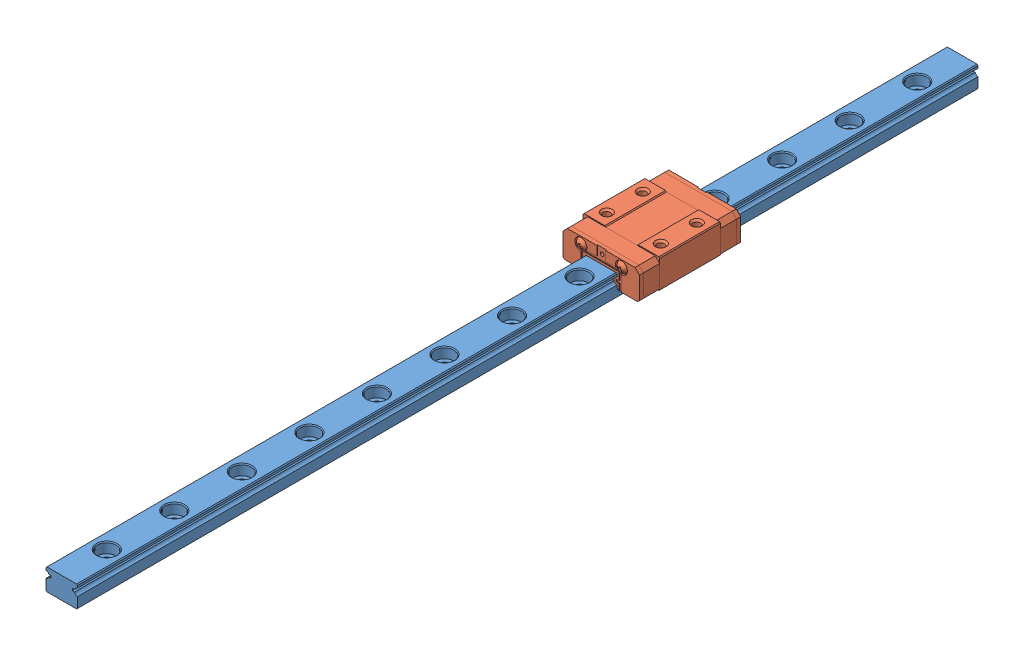
SolidWorks assembly MGN7_wRail, configuration Default. Lengths in mm.
Overall size (17 8.1 200).
2 component instances, 2 part files, 0 mates.
Components (placement in the parent):
- MGN7_Rail-1: MGN7_Rail [200mm] at origin size (7 4.8 200)
- MGN7C_Carriage-1: MGN7C_Carriage [Default] at (0 2.45 63.9441) size (17 6.5 23.48)
